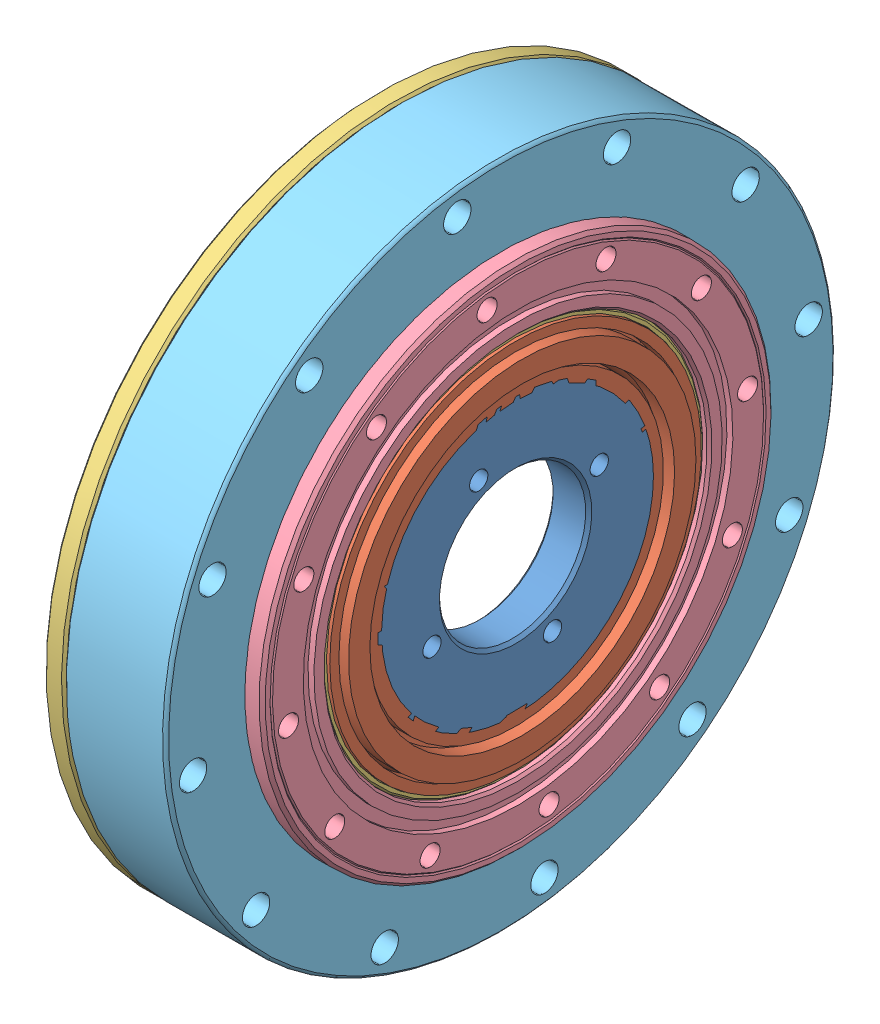
SolidWorks assembly shd-25-xxx-2sh, configuration Default. Lengths in mm.
5 component instances, 5 part files, 10 mates.
Components (placement in the parent):
- SHD-25-2SH-WG-1: SHD-25-2SH-WG [Default] at (4.9014 0.6016 48.7653) x (1 0 0) z (0 0.914874 0.40374) size (6.35 45.22 45.22)
- 25 WG BEARING DS-1: 25 WG BEARING DS [Default] at (4.9014 0.6016 48.7653) x (1 0 0) z (0 -0.12248 0.992471) size (8.52 61 61)
- SHD-25-2SH-FS-1: SHD-25-2SH-FS [Default] at (-11.1703 0.6016 48.7653) x (1 0 0) z (0 0.990129 0.14016) size (22 110 110)
- SHD-25-2SH-CS-1: SHD-25-2SH-CS [Default] at (-7.0486 0.6016 48.7653) x (1 0 0) z (0 -0.13377 0.991012) size (18.7 110 110)
- SHD-25-2SH-FS2-1: SHD-25-2SH-FS2 [Default] at (-7.8703 0.6016 48.7653) x (1 0 0) z (0 0.990129 0.14016) size (16.7 110 110)
Mates (geometry in assembly coordinates):
- Distance1: distance = 0 mm aligned: plane of SHD-25-2SH-WG-1 through (11.2514 5.6483 37.3294) normal (1 0 0); plane of 25 WG BEARING DS-1 through (11.2514 22.4359 51.4599) normal (1 0 0)
- Distance3: distance = 1.6 mm aligned: plane of SHD-25-2SH-WG-1 through (11.2514 5.6483 37.3294) normal (1 0 0); plane of SHD-25-2SH-CS-1 through (9.6514 0.6016 48.7653) normal (1 0 0)
- Concentric1: concentric aligned: cylinder of SHD-25-2SH-WG-1 through (-0.1986 0.6016 48.7653) axis (-1 0 0) radius 12; cylinder of 25 WG BEARING DS-1 through (4.9014 0.6016 48.7653) axis (-1 0 0) radius 22
- Concentric2: concentric aligned: cylinder of SHD-25-2SH-WG-1 through (-0.1986 0.6016 48.7653) axis (-1 0 0) radius 12; cylinder of SHD-25-2SH-FS-1 through (-16.2703 0.6016 48.7653) axis (-1 0 0) radius 30.5
- Concentric3: concentric aligned: cylinder of SHD-25-2SH-WG-1 through (-0.1986 0.6016 48.7653) axis (-1 0 0) radius 12; cylinder of SHD-25-2SH-CS-1 through (-12.1486 0.6016 48.7653) axis (-1 0 0) radius 31.4188
- Distance4: distance = 22.4217 mm anti-aligned: plane of SHD-25-2SH-WG-1 through (11.2514 5.6483 37.3294) normal (1 0 0); plane of SHD-25-2SH-FS-1 through (-11.1703 6.8247 4.8036) normal (-1 0 0)
- Concentric5: concentric anti-aligned: cylinder of SHD-25-2SH-WG-1 through (-0.1986 0.6016 48.7653) axis (-1 0 0) radius 12; circle of SHD-25-2SH-FS2-1
- Coincident5: coincident anti-aligned: plane of SHD-25-2SH-FS-1 through (-7.8703 5.176 16.4505) normal (1 0 0); plane of SHD-25-2SH-FS2-1 through (-7.8703 0.6016 48.7653) normal (-1 0 0)
- Concentric6: concentric anti-aligned: cylinder of SHD-25-2SH-FS-1 through (-11.1703 47.907 29.7075) axis (-1 0 0) radius 2.25; cylinder of SHD-25-2SH-FS2-1 through (8.8297 47.907 29.7075) axis (1 0 0) radius 2.25
- GearMate1: gear = 83.9997 : 1 mm: cylinder of SHD-25-2SH-WG-1 through (-0.1986 0.6016 48.7653) axis (-1 0 0) radius 12; cylinder of SHD-25-2SH-CS-1 through (-7.0586 0.6016 48.7653) axis (1 0 0) radius 41.9998
